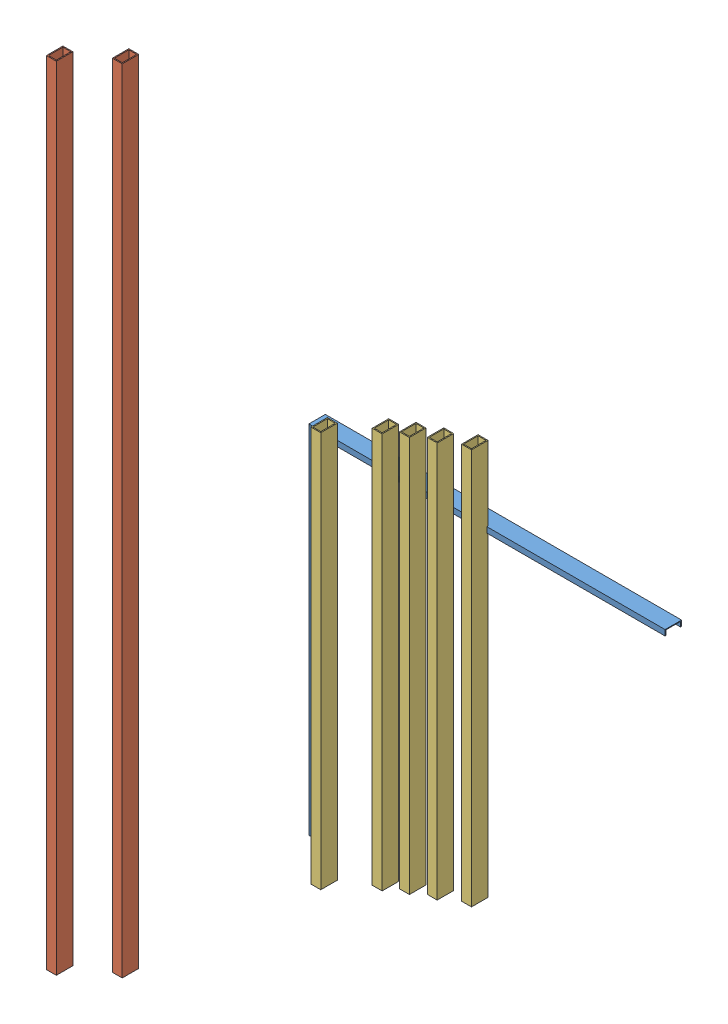
SolidWorks assembly Base, configuration Default. Lengths in mm.
Overall size (3608.79 6138.05 1282.33).
9 component instances, 3 part files, 5 mates.
Components (placement in the parent):
- LongCChannel-1: LongCChannel [Default] at (389.5751 -1032.3142 495.7655) size (43.18 2743.2 127)
- LongCChannel-2: LongCChannel [Default] at (3132.5368 1711.1242 368.7655) x (0 -1 0) z (0 0 -1) size (43.18 2743.2 127)
- LongBeam-1: LongBeam [Default] at (-162.6051 -1741.3826 1457.0234) size (76.2 6096 127)
- LongBeam-2: LongBeam [Default] at (-476.2491 -1783.4372 1651.1003) size (76.2 6096 127)
- MediumBeam-1: MediumBeam [Default] at (1148.013 -606.8013 1238.9657) size (76.2 3048 127)
- MediumBeam-2: MediumBeam [Default] at (1172.02 -827.0143 790.3636) size (76.2 3048 127)
- MediumBeam-3: MediumBeam [Default] at (1325.1324 -802.7947 733.6025) size (76.2 3048 127)
- MediumBeam-4: MediumBeam [Default] at (1485.4953 -786.2744 680.0688) size (76.2 3048 127)
- MediumBeam-5: MediumBeam [Default] at (1683.56 -765.9064 613.8808) size (76.2 3048 127)
Mates (geometry in assembly coordinates):
- Coincident1: coincident anti-aligned: plane of LongCChannel-1 through (389.5751 1710.8858 368.7655) normal (0.707107 0.707107 0); plane of LongCChannel-2 through (389.3368 1711.1242 495.7655) normal (-0.707107 -0.707107 0)
- Perpendicular1: perpendicular: plane of LongCChannel-1 through (389.5751 1710.8858 368.7655) normal (-1 0 0); plane of LongCChannel-2 through (389.3368 1711.1242 495.7655) normal (0 1 0)
- Coincident4: coincident aligned: plane of LongCChannel-1 through (432.7551 1710.8858 368.7655) normal (0 0 -1); plane of LongCChannel-2 through (389.3368 1711.1242 368.7655) normal (0 0 -1)
- Coincident6: coincident anti-aligned: plane of LongCChannel-1 through (389.5751 1710.8858 368.7655) normal (0.707107 0.707107 0); plane of LongCChannel-2 through (389.3368 1711.1242 495.7655) normal (-0.707107 -0.707107 0)
- Coincident7: coincident aligned: plane of LongCChannel-1 through (432.7551 1710.8858 368.7655) normal (0 0 -1); plane of LongCChannel-2 through (389.3368 1711.1242 368.7655) normal (0 0 -1)
